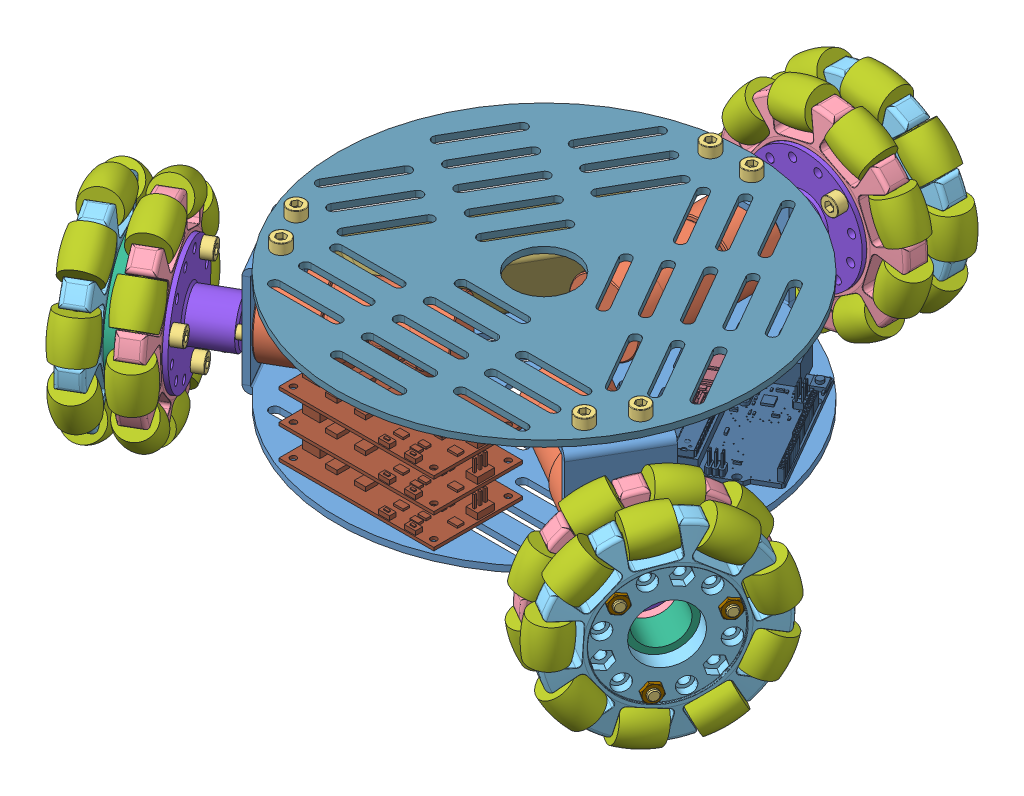
SolidWorks assembly mo-hinh-robot-new, configuration Default. Lengths in mm.
Overall size (364.36 149.81 350).
113 component instances, 14 part files, 37 mates.
Components (placement in the parent):
- khung duoi-1-2: khung duoi-1 [Default] at (-15.7838 -23.5823 19.2294) size (200 53 201.72)
- DC 12v 251rpm-1: DC 12v 251rpm [Default] at (-101.2746 -4.3589 68.5875) x (0.866025 0 -0.5) z (-0.5 0 -0.866025) size (90.8 37 37)
- socket head cap screw_iso-2: socket head cap screw_iso [ISO 4762 M3 x 5 - 5N] at (-98.7207 -4.3589 85.0109) x (0.866025 0 -0.5) z (0.5 0 0.866025) size (8 5.5 5.5)
- socket head cap screw_iso-3: socket head cap screw_iso [ISO 4762 M3 x 5 - 5N] at (-114.2207 -4.3589 58.1641) x (0.866025 0 -0.5) z (0.5 0 0.866025) size (8 5.5 5.5)
- banhxe-1: banhxe [Default] at (-204.1499 -59.7221 94.9057) x (-0.487142 0.225323 -0.843755) z (0.866025 0 -0.5) size (124.48 124.98 61.51)
  - omniwheel_1-1: omniwheel_1 [Default] at (-17.0114 53.5739 73.2518) size (91.98 90.63 15.09)
  - omniwheel_2-1: omniwheel_2 [Default] at (-17.0114 53.5739 37.2518) x (-0.5 -0.866025 0) z (0 0 -1) size (91.98 90.63 15.09)
  - Part1^banhxe-1: Part1^banhxe [Default] at (-17.0114 53.5739 59.2518) x (-1 0 0) z (0 0 -1) size (56.8 56.8 18) (virtual)
  - roller-1: roller [Default] at (-17.0114 132.3987 78.8462) x (1 0 0) z (0 0.323318 -0.94629) size (24.1 19 19)
  - roller-3: roller [Default] at (33.6561 113.9572 78.8462) x (0.766044 -0.642788 0) z (0.207825 0.247676 -0.94629) size (24.1 19 19)
  - roller-4: roller [Default] at (60.6158 67.2617 78.8462) x (0.173648 -0.984808 0) z (0.318406 0.056144 -0.94629) size (24.1 19 19)
  - roller-5: roller [Default] at (51.2528 14.1616 78.8462) x (-0.5 -0.866025 0) z (0.280001 -0.161659 -0.94629) size (24.1 19 19)
  - roller-6: roller [Default] at (9.9482 -20.4971 78.8462) x (-0.939693 -0.34202 0) z (0.110581 -0.303819 -0.94629) size (24.1 19 19)
  - roller-7: roller [Default] at (-43.9711 -20.4971 78.8462) x (-0.939693 0.34202 0) z (-0.110581 -0.303819 -0.94629) size (24.1 19 19)
  - roller-8: roller [Default] at (-85.2757 14.1616 78.8462) x (-0.5 0.866025 0) z (-0.280001 -0.161659 -0.94629) size (24.1 19 19)
  - roller-9: roller [Default] at (-94.6387 67.2617 78.8462) x (0.173648 0.984808 0) z (-0.318406 0.056144 -0.94629) size (24.1 19 19)
  - roller-10: roller [Default] at (-67.679 113.9572 78.8462) x (0.766044 0.642788 0) z (-0.207825 0.247676 -0.94629) size (24.1 19 19)
  - roller-11: roller [Default] at (-17.5454 53.8822 51.7918) x (0.5 0.866025 0) z (-0.150538 0.086913 0.984776) size (24.1 19 19)
  - roller-12: roller [Default] at (-17.6186 53.4669 51.7918) x (-0.173648 0.984808 0) z (-0.171186 -0.030185 0.984776) size (24.1 19 19)
  - roller-13: roller [Default] at (-17.4078 53.1016 51.7918) x (-0.766044 0.642788 0) z (-0.111734 -0.133159 0.984776) size (24.1 19 19)
  - roller-14: roller [Default] at (-17.0114 52.9574 51.7918) x (-1 0 0) z (0 -0.173827 0.984776) size (24.1 19 19)
  - roller-15: roller [Default] at (-16.6151 53.1016 51.7918) x (-0.766044 -0.642788 0) z (0.111734 -0.133159 0.984776) size (24.1 19 19)
  - roller-16: roller [Default] at (-16.4042 53.4669 51.7918) x (-0.173648 -0.984808 0) z (0.171186 -0.030185 0.984776) size (24.1 19 19)
  - roller-17: roller [Default] at (-16.4775 53.8822 51.7918) x (0.5 -0.866025 0) z (0.150538 0.086913 0.984776) size (24.1 19 19)
  - roller-18: roller [Default] at (-16.8006 54.1533 51.7918) x (0.939693 -0.34202 0) z (0.059452 0.163344 0.984776) size (24.1 19 19)
  - roller-19: roller [Default] at (-17.2223 54.1533 51.7918) x (0.939693 0.34202 0) z (-0.059452 0.163344 0.984776) size (24.1 19 19)
  - Part3^banhxe-1: Part3^banhxe [Default] at (-17.0114 53.5739 72.2518) size (56.8 56.8 23)
  - socket head cap screw_iso-2: socket head cap screw_iso [ISO 4762 M5 x 40 - 22C] at (-37.6228 65.4739 80.2518) x (0 0 -1) z (-0.98661 0.163099 0) size (45 8.5 8.5)
  - hex nut gradec_iso-1: hex nut gradec_iso [ISO - 4034 - M5 - N] at (-37.6228 65.4739 36.6518) x (0 -1 0) z (0 0 -1) size (8 9.24 5.6)
  - hex nut gradec_iso-2: hex nut gradec_iso [ISO - 4034 - M5 - N] at (-17.0114 29.7739 36.6518) x (0.866025 0.5 0) z (0 0 -1) size (8 9.24 5.6)
  - hex nut gradec_iso-3: hex nut gradec_iso [ISO - 4034 - M5 - N] at (3.6 65.4739 36.6518) x (-0.866025 0.5 0) z (0 0 -1) size (8 9.24 5.6)
  - socket head cap screw_iso-3: socket head cap screw_iso [ISO 4762 M5 x 40 - 22C] at (-17.0114 29.7739 80.2518) x (0 0 -1) z (0.352057 -0.935979 0) size (45 8.5 8.5)
  - socket head cap screw_iso-4: socket head cap screw_iso [ISO 4762 M5 x 40 - 22C] at (3.6 65.4739 80.2518) x (0 0 -1) z (0.634553 0.77288 0) size (45 8.5 8.5)
  - socket head cap screw_iso-7: socket head cap screw_iso [ISO 4762 M3 x 10 - 10C] at (-17.0114 39.5739 87.2518) x (0 1 0) z (-0.678428 0 0.734667) size (13 5.5 5.5)
- DC 12v 251rpm-2: DC 12v 251rpm [Default] at (69.7069 -4.3589 68.5875) x (-0.866025 0 -0.5) z (-0.5 0 0.866025) size (90.8 37 37)
- DC 12v 251rpm-3: DC 12v 251rpm [Default] at (-15.7838 -4.3589 -79.4868) x (0 0 1) z (1 0 0) size (90.8 37 37)
- socket head cap screw_iso-4: socket head cap screw_iso [ISO 4762 M3 x 5 - 5N] at (67.153 -4.3589 85.0109) x (-0.866025 0 -0.5) z (0.5 0 -0.866025) size (8 5.5 5.5)
- socket head cap screw_iso-5: socket head cap screw_iso [ISO 4762 M3 x 5 - 5N] at (-0.2838 -4.3589 -85.4868) x (0 0 1) z (-1 0 0) size (8 5.5 5.5)
- socket head cap screw_iso-6: socket head cap screw_iso [ISO 4762 M3 x 5 - 5N] at (82.653 -4.3589 58.1641) x (-0.866025 0 -0.5) z (0.5 0 -0.866025) size (8 5.5 5.5)
- socket head cap screw_iso-7: socket head cap screw_iso [ISO 4762 M3 x 5 - 5N] at (-31.2838 -4.3589 -85.4868) x (0 0 1) z (-1 0 0) size (8 5.5 5.5)
- banhxe-2: banhxe [Default] at (143.9368 -59.7221 144.5211) x (-0.487142 0.225323 0.843755) z (-0.866025 0 -0.5) size (124.48 124.98 61.51)
  - omniwheel_1-1: omniwheel_1 [Default] at (-17.0114 53.5739 73.2518) size (91.98 90.63 15.09)
  - omniwheel_2-1: omniwheel_2 [Default] at (-17.0114 53.5739 37.2518) x (-0.5 -0.866025 0) z (0 0 -1) size (91.98 90.63 15.09)
  - Part1^banhxe-1: Part1^banhxe [Default] at (-17.0114 53.5739 59.2518) x (-1 0 0) z (0 0 -1) size (56.8 56.8 18) (virtual)
  - roller-1: roller [Default] at (-17.0114 132.3987 78.8462) x (1 0 0) z (0 0.323318 -0.94629) size (24.1 19 19)
  - roller-3: roller [Default] at (33.6561 113.9572 78.8462) x (0.766044 -0.642788 0) z (0.207825 0.247676 -0.94629) size (24.1 19 19)
  - roller-4: roller [Default] at (60.6158 67.2617 78.8462) x (0.173648 -0.984808 0) z (0.318406 0.056144 -0.94629) size (24.1 19 19)
  - roller-5: roller [Default] at (51.2528 14.1616 78.8462) x (-0.5 -0.866025 0) z (0.280001 -0.161659 -0.94629) size (24.1 19 19)
  - roller-6: roller [Default] at (9.9482 -20.4971 78.8462) x (-0.939693 -0.34202 0) z (0.110581 -0.303819 -0.94629) size (24.1 19 19)
  - roller-7: roller [Default] at (-43.9711 -20.4971 78.8462) x (-0.939693 0.34202 0) z (-0.110581 -0.303819 -0.94629) size (24.1 19 19)
  - roller-8: roller [Default] at (-85.2757 14.1616 78.8462) x (-0.5 0.866025 0) z (-0.280001 -0.161659 -0.94629) size (24.1 19 19)
  - roller-9: roller [Default] at (-94.6387 67.2617 78.8462) x (0.173648 0.984808 0) z (-0.318406 0.056144 -0.94629) size (24.1 19 19)
  - roller-10: roller [Default] at (-67.679 113.9572 78.8462) x (0.766044 0.642788 0) z (-0.207825 0.247676 -0.94629) size (24.1 19 19)
  - roller-11: roller [Default] at (-17.5454 53.8822 51.7918) x (0.5 0.866025 0) z (-0.150538 0.086913 0.984776) size (24.1 19 19)
  - roller-12: roller [Default] at (-17.6186 53.4669 51.7918) x (-0.173648 0.984808 0) z (-0.171186 -0.030185 0.984776) size (24.1 19 19)
  - roller-13: roller [Default] at (-17.4078 53.1016 51.7918) x (-0.766044 0.642788 0) z (-0.111734 -0.133159 0.984776) size (24.1 19 19)
  - roller-14: roller [Default] at (-17.0114 52.9574 51.7918) x (-1 0 0) z (0 -0.173827 0.984776) size (24.1 19 19)
  - roller-15: roller [Default] at (-16.6151 53.1016 51.7918) x (-0.766044 -0.642788 0) z (0.111734 -0.133159 0.984776) size (24.1 19 19)
  - roller-16: roller [Default] at (-16.4042 53.4669 51.7918) x (-0.173648 -0.984808 0) z (0.171186 -0.030185 0.984776) size (24.1 19 19)
  - roller-17: roller [Default] at (-16.4775 53.8822 51.7918) x (0.5 -0.866025 0) z (0.150538 0.086913 0.984776) size (24.1 19 19)
  - roller-18: roller [Default] at (-16.8006 54.1533 51.7918) x (0.939693 -0.34202 0) z (0.059452 0.163344 0.984776) size (24.1 19 19)
  - roller-19: roller [Default] at (-17.2223 54.1533 51.7918) x (0.939693 0.34202 0) z (-0.059452 0.163344 0.984776) size (24.1 19 19)
  - Part3^banhxe-1: Part3^banhxe [Default] at (-17.0114 53.5739 72.2518) size (56.8 56.8 23)
  - socket head cap screw_iso-2: socket head cap screw_iso [ISO 4762 M5 x 40 - 22C] at (-37.6228 65.4739 80.2518) x (0 0 -1) z (-0.98661 0.163099 0) size (45 8.5 8.5)
  - hex nut gradec_iso-1: hex nut gradec_iso [ISO - 4034 - M5 - N] at (-37.6228 65.4739 36.6518) x (0 -1 0) z (0 0 -1) size (8 9.24 5.6)
  - hex nut gradec_iso-2: hex nut gradec_iso [ISO - 4034 - M5 - N] at (-17.0114 29.7739 36.6518) x (0.866025 0.5 0) z (0 0 -1) size (8 9.24 5.6)
  - hex nut gradec_iso-3: hex nut gradec_iso [ISO - 4034 - M5 - N] at (3.6 65.4739 36.6518) x (-0.866025 0.5 0) z (0 0 -1) size (8 9.24 5.6)
  - socket head cap screw_iso-3: socket head cap screw_iso [ISO 4762 M5 x 40 - 22C] at (-17.0114 29.7739 80.2518) x (0 0 -1) z (0.352057 -0.935979 0) size (45 8.5 8.5)
  - socket head cap screw_iso-4: socket head cap screw_iso [ISO 4762 M5 x 40 - 22C] at (3.6 65.4739 80.2518) x (0 0 -1) z (0.634553 0.77288 0) size (45 8.5 8.5)
  - socket head cap screw_iso-7: socket head cap screw_iso [ISO 4762 M3 x 10 - 10C] at (-17.0114 39.5739 87.2518) x (0 1 0) z (-0.678428 0 0.734667) size (13 5.5 5.5)
- banhxe-3: banhxe [Default] at (12.8616 -59.7221 -181.7386) x (0.974284 0.225323 0) z (0 0 1) size (124.48 124.98 61.51)
  - omniwheel_1-1: omniwheel_1 [Default] at (-17.0114 53.5739 73.2518) size (91.98 90.63 15.09)
  - omniwheel_2-1: omniwheel_2 [Default] at (-17.0114 53.5739 37.2518) x (-0.5 -0.866025 0) z (0 0 -1) size (91.98 90.63 15.09)
  - Part1^banhxe-1: Part1^banhxe [Default] at (-17.0114 53.5739 59.2518) x (-1 0 0) z (0 0 -1) size (56.8 56.8 18) (virtual)
  - roller-1: roller [Default] at (-17.0114 132.3987 78.8462) x (1 0 0) z (0 0.323318 -0.94629) size (24.1 19 19)
  - roller-3: roller [Default] at (33.6561 113.9572 78.8462) x (0.766044 -0.642788 0) z (0.207825 0.247676 -0.94629) size (24.1 19 19)
  - roller-4: roller [Default] at (60.6158 67.2617 78.8462) x (0.173648 -0.984808 0) z (0.318406 0.056144 -0.94629) size (24.1 19 19)
  - roller-5: roller [Default] at (51.2528 14.1616 78.8462) x (-0.5 -0.866025 0) z (0.280001 -0.161659 -0.94629) size (24.1 19 19)
  - roller-6: roller [Default] at (9.9482 -20.4971 78.8462) x (-0.939693 -0.34202 0) z (0.110581 -0.303819 -0.94629) size (24.1 19 19)
  - roller-7: roller [Default] at (-43.9711 -20.4971 78.8462) x (-0.939693 0.34202 0) z (-0.110581 -0.303819 -0.94629) size (24.1 19 19)
  - roller-8: roller [Default] at (-85.2757 14.1616 78.8462) x (-0.5 0.866025 0) z (-0.280001 -0.161659 -0.94629) size (24.1 19 19)
  - roller-9: roller [Default] at (-94.6387 67.2617 78.8462) x (0.173648 0.984808 0) z (-0.318406 0.056144 -0.94629) size (24.1 19 19)
  - roller-10: roller [Default] at (-67.679 113.9572 78.8462) x (0.766044 0.642788 0) z (-0.207825 0.247676 -0.94629) size (24.1 19 19)
  - roller-11: roller [Default] at (-17.5454 53.8822 51.7918) x (0.5 0.866025 0) z (-0.150538 0.086913 0.984776) size (24.1 19 19)
  - roller-12: roller [Default] at (-17.6186 53.4669 51.7918) x (-0.173648 0.984808 0) z (-0.171186 -0.030185 0.984776) size (24.1 19 19)
  - roller-13: roller [Default] at (-17.4078 53.1016 51.7918) x (-0.766044 0.642788 0) z (-0.111734 -0.133159 0.984776) size (24.1 19 19)
  - roller-14: roller [Default] at (-17.0114 52.9574 51.7918) x (-1 0 0) z (0 -0.173827 0.984776) size (24.1 19 19)
  - roller-15: roller [Default] at (-16.6151 53.1016 51.7918) x (-0.766044 -0.642788 0) z (0.111734 -0.133159 0.984776) size (24.1 19 19)
  - roller-16: roller [Default] at (-16.4042 53.4669 51.7918) x (-0.173648 -0.984808 0) z (0.171186 -0.030185 0.984776) size (24.1 19 19)
  - roller-17: roller [Default] at (-16.4775 53.8822 51.7918) x (0.5 -0.866025 0) z (0.150538 0.086913 0.984776) size (24.1 19 19)
  - roller-18: roller [Default] at (-16.8006 54.1533 51.7918) x (0.939693 -0.34202 0) z (0.059452 0.163344 0.984776) size (24.1 19 19)
  - roller-19: roller [Default] at (-17.2223 54.1533 51.7918) x (0.939693 0.34202 0) z (-0.059452 0.163344 0.984776) size (24.1 19 19)
  - Part3^banhxe-1: Part3^banhxe [Default] at (-17.0114 53.5739 72.2518) size (56.8 56.8 23)
  - socket head cap screw_iso-2: socket head cap screw_iso [ISO 4762 M5 x 40 - 22C] at (-37.6228 65.4739 80.2518) x (0 0 -1) z (-0.98661 0.163099 0) size (45 8.5 8.5)
  - hex nut gradec_iso-1: hex nut gradec_iso [ISO - 4034 - M5 - N] at (-37.6228 65.4739 36.6518) x (0 -1 0) z (0 0 -1) size (8 9.24 5.6)
  - hex nut gradec_iso-2: hex nut gradec_iso [ISO - 4034 - M5 - N] at (-17.0114 29.7739 36.6518) x (0.866025 0.5 0) z (0 0 -1) size (8 9.24 5.6)
  - hex nut gradec_iso-3: hex nut gradec_iso [ISO - 4034 - M5 - N] at (3.6 65.4739 36.6518) x (-0.866025 0.5 0) z (0 0 -1) size (8 9.24 5.6)
  - socket head cap screw_iso-3: socket head cap screw_iso [ISO 4762 M5 x 40 - 22C] at (-17.0114 29.7739 80.2518) x (0 0 -1) z (0.352057 -0.935979 0) size (45 8.5 8.5)
  - socket head cap screw_iso-4: socket head cap screw_iso [ISO 4762 M5 x 40 - 22C] at (3.6 65.4739 80.2518) x (0 0 -1) z (0.634553 0.77288 0) size (45 8.5 8.5)
  - socket head cap screw_iso-7: socket head cap screw_iso [ISO 4762 M3 x 10 - 10C] at (-17.0114 39.5739 87.2518) x (0 1 0) z (-0.678428 0 0.734667) size (13 5.5 5.5)
- Arduino UNO-1: Arduino UNO [Predeterminado] at (41.1207 -23.5823 -18.8206) x (0.5 0 0.866025) z (-0.866025 0 0.5) size (75 12 51.02)
- DRIVER-cytron-1: DRIVER-cytron [Default] at (-53.2838 -23.5823 110.0884) size (75 10.5 43)
- DRIVER-cytron-2: DRIVER-cytron [Default] at (-53.2838 -8.5823 110.0884) size (75 10.5 43)
- DRIVER-cytron-3: DRIVER-cytron [Default] at (-53.2838 6.4177 110.0884) size (75 10.5 43)
- pin li-po-1: pin li-po [Default] at (-73.3745 -23.5823 -14.0206) x (0.5 0 -0.866025) z (0.866025 0 0.5) size (105 23 32)
- HC-06-1: HC-06 [Predeterminado] at (34.603 -3.5823 -8.8739) x (0.5 0 0.866025) z (-0.866025 0 0.5) size (42.75 6.1 15)
- khung tren-2: khung tren [Default] at (-15.7838 26.4211 19.2294) size (200 3 200)
- socket head cap screw_iso-8: socket head cap screw_iso [ISO 4762 M5 x 8 - 8N] at (-89.1905 34.4211 73.1578) x (0 -1 0) z (0 0 1) size (13 8.5 8.5)
- socket head cap screw_iso-9: socket head cap screw_iso [ISO 4762 M5 x 8 - 8N] at (-99.1905 34.4211 55.8373) x (0 -1 0) z (0 0 1) size (13 8.5 8.5)
- socket head cap screw_iso-10: socket head cap screw_iso [ISO 4762 M5 x 8 - 8N] at (67.6228 34.4211 55.8373) x (0 -1 0) z (0 0 1) size (13 8.5 8.5)
- socket head cap screw_iso-11: socket head cap screw_iso [ISO 4762 M5 x 8 - 8N] at (57.6228 34.4211 73.1578) x (0 -1 0) z (0 0 1) size (13 8.5 8.5)
- socket head cap screw_iso-12: socket head cap screw_iso [ISO 4762 M5 x 8 - 8N] at (-25.7838 34.4211 -71.3068) x (0 -1 0) z (0 0 1) size (13 8.5 8.5)
- socket head cap screw_iso-13: socket head cap screw_iso [ISO 4762 M5 x 8 - 8N] at (-5.7838 34.4211 -71.3068) x (0 -1 0) z (0 0 1) size (13 8.5 8.5)
Mates (geometry in assembly coordinates):
- Concentric1: concentric aligned: cylinder of khung duoi-1-2 through (-103.8726 -11.3589 70.0875) axis (0.866025 0 -0.5) radius 6.2; cylinder of DC 12v 251rpm-1 through (-106.2975 -11.3589 71.4875) axis (0.866025 0 -0.5) radius 6
- Coincident1: coincident anti-aligned: plane of khung duoi-1-2 through (-101.2746 -124.3385 68.5875) normal (0.866025 0 -0.5); plane of DC 12v 251rpm-1 through (-101.2746 -4.3589 68.5875) normal (-0.866025 0 0.5)
- Concentric2: concentric anti-aligned: circle of khung duoi-1-2; circle of DC 12v 251rpm-1
- Concentric3: concentric anti-aligned: cylinder of khung duoi-1-2 through (-96.1226 -4.3589 83.5109) axis (0.866025 0 -0.5) radius 1.6; cylinder of socket head cap screw_iso-2 through (-126.217 -4.3589 100.8859) axis (-0.866025 0 0.5) radius 2.75
- Coincident3: coincident anti-aligned: plane of khung duoi-1-2 through (-103.8726 -124.3385 70.0875) normal (-0.866025 0 0.5); plane of socket head cap screw_iso-2 through (-96.1226 -1.6089 83.5109) normal (0.866025 0 -0.5)
- Concentric4: concentric anti-aligned: cylinder of khung duoi-1-2 through (-111.6226 -4.3589 56.6641) axis (0.866025 0 -0.5) radius 1.6; cylinder of socket head cap screw_iso-3 through (-141.717 -4.3589 74.0391) axis (-0.866025 0 0.5) radius 2.75
- Coincident4: coincident anti-aligned: plane of khung duoi-1-2 through (-103.8726 -124.3385 70.0875) normal (-0.866025 0 0.5); plane of socket head cap screw_iso-3 through (-111.6226 -1.6089 56.6641) normal (0.866025 0 -0.5)
- Concentric5: concentric aligned: cylinder of DC 12v 251rpm-1 through (-119.4611 -11.3589 79.0875) axis (0.866025 0 -0.5) radius 3; cylinder of banhxe-1/Part3^banhxe-1 through (-127.2553 -11.3589 83.5875) axis (0.866025 0 -0.5) radius 3
- Distance1: distance = 4 mm anti-aligned: plane of khung duoi-1-2 through (-103.8726 -124.3385 70.0875) normal (-0.866025 0 0.5); plane of banhxe-1/Part3^banhxe-1 through (-107.3367 -11.3589 72.0875) normal (0.866025 0 -0.5)
- Coincident6: coincident anti-aligned: plane of khung duoi-1-2 through (-15.7838 -23.5823 19.2294) normal (0 1 0); plane of DRIVER-cytron-1 through (-53.2838 -23.5823 110.0884) normal (0 -1 0)
- Tangent3: tangent aligned: plane of khung duoi-1-2 through (44.2162 -26.5823 72.0884) normal (0 0 1); cylinder of DRIVER-cytron-1 through (18.2162 -23.5823 70.5884) axis (0 1 0) radius 1.5
- Tangent4: tangent aligned: plane of khung duoi-1-2 through (-45.7838 -26.5823 72.0884) normal (0 0 1); cylinder of DRIVER-cytron-1 through (-49.7838 -23.5823 70.5884) axis (0 1 0) radius 1.5
- Width1: width anti-aligned: plane of khung duoi-1-2 through (4.2162 26.4211 -61.3068) normal (1 0 0); plane of khung duoi-1-2 through (-35.7838 26.4211 -131.3068) normal (-1 0 0); plane of DRIVER-cytron-1 through (-53.2838 -22.0823 110.0884) normal (-1 0 0); plane of DRIVER-cytron-1 through (21.7162 -22.0823 110.0884) normal (1 0 0)
- Coincident7: coincident anti-aligned: plane of khung duoi-1-2 through (-15.7838 -23.5823 19.2294) normal (0 1 0); plane of Arduino UNO-1 through (41.1207 -23.5823 -18.8206) normal (0 -1 0)
- Coincident8: coincident aligned: plane of khung duoi-1-2 through (13.5222 -26.5823 -15.011) normal (-0.866025 0 0.5); plane of Arduino UNO-1 through (27.0292 -32.5823 8.3838) normal (-0.866025 0 0.5)
- Distance2: distance = 3 mm: line of khung duoi-1-2 through (57.9838 -26.5823 11.2807) axis (0 1 0); plane of Arduino UNO-1 through (82.3874 -21.5823 0.6553) normal (0.5 0 0.866025)
- Coincident9: coincident anti-aligned: plane of khung duoi-1-2 through (-15.7838 -23.5823 19.2294) normal (0 1 0); plane of pin li-po-1 through (-73.3745 -23.5823 -14.0206) normal (0 -1 0)
- Coincident10: coincident aligned: plane of khung duoi-1-2 through (-94.7309 -26.5823 -9.0302) normal (-0.866025 0 -0.5); plane of pin li-po-1 through (-113.4809 -0.5823 23.4457) normal (-0.866025 0 -0.5)
- Width2: width aligned: plane of pin li-po-1 through (-85.7681 -0.5823 39.4457) normal (-0.5 0 0.866025); plane of pin li-po-1 through (-33.2681 -0.5823 -51.4869) normal (0.5 0 -0.866025); plane of khung duoi-1-2 through (43.9626 26.4211 76.818) normal (-0.5 0 0.866025); plane of khung duoi-1-2 through (124.5844 26.4211 77.177) normal (0.5 0 -0.866025)
- Distance3: distance = 20 mm anti-aligned: plane of HC-06-1 through (34.603 -3.5823 -8.8739) normal (0 -1 0); plane of khung duoi-1-2 through (-15.7838 -23.5823 19.2294) normal (0 1 0)
- Width3: width aligned: plane of HC-06-1 through (50.5982 -1.5823 3.8306) normal (0.866025 0 -0.5); plane of HC-06-1 through (18.6078 -1.5823 -21.5784) normal (-0.866025 0 0.5); plane of Arduino UNO-1 through (35.1153 -17.5823 -17.7723) normal (0.866025 0 -0.5); plane of Arduino UNO-1 through (26.6405 -17.5823 -12.8794) normal (-0.866025 0 0.5)
- Distance4: distance = 10 mm aligned: plane of HC-06-1 through (37.6078 -1.5823 11.3306) normal (0.5 0 0.866025); plane of Arduino UNO-1 through (53.3404 -17.5823 13.7944) normal (0.5 0 0.866025)
- Coincident11: coincident anti-aligned: plane of khung duoi-1-2 through (199.4372 26.4211 143.4873) normal (0 1 0); plane of khung tren-2 through (-15.7838 26.4211 19.2294) normal (0 -1 0)
- Coincident12: coincident aligned: plane of khung duoi-1-2 through (44.2162 -26.5823 72.0884) normal (0 0 1); plane of khung tren-2 through (44.2162 26.4211 72.0884) normal (0 0 1)
- Concentric6: concentric aligned: circle of khung duoi-1-2; circle of khung tren-2
- Concentric7: concentric aligned: cylinder of khung tren-2 through (-89.1905 26.4211 73.1578) axis (0 1 0) radius 2.1; cylinder of socket head cap screw_iso-8 through (-89.1905 66.1711 73.1578) axis (0 1 0) radius 4.25
- Coincident13: coincident anti-aligned: plane of khung tren-2 through (-15.7838 29.4211 19.2294) normal (0 1 0); plane of socket head cap screw_iso-8 through (-84.9405 29.4211 73.1578) normal (0 -1 0)
- Concentric8: concentric aligned: cylinder of khung tren-2 through (-99.1905 26.4211 55.8373) axis (0 1 0) radius 2.1; cylinder of socket head cap screw_iso-9 through (-99.1905 66.1711 55.8373) axis (0 1 0) radius 4.25
- Coincident14: coincident anti-aligned: plane of khung tren-2 through (-15.7838 29.4211 19.2294) normal (0 1 0); plane of socket head cap screw_iso-9 through (-94.9405 29.4211 55.8373) normal (0 -1 0)
- Concentric9: concentric aligned: cylinder of khung tren-2 through (67.6228 26.4211 55.8373) axis (0 1 0) radius 2.1; cylinder of socket head cap screw_iso-10 through (67.6228 66.1711 55.8373) axis (0 1 0) radius 4.25
- Coincident15: coincident anti-aligned: plane of khung tren-2 through (-15.7838 29.4211 19.2294) normal (0 1 0); plane of socket head cap screw_iso-10 through (71.8728 29.4211 55.8373) normal (0 -1 0)
- Concentric10: concentric aligned: cylinder of khung tren-2 through (57.6228 26.4211 73.1578) axis (0 1 0) radius 2.1; cylinder of socket head cap screw_iso-11 through (57.6228 66.1711 73.1578) axis (0 1 0) radius 4.25
- Coincident16: coincident anti-aligned: plane of khung tren-2 through (-15.7838 29.4211 19.2294) normal (0 1 0); plane of socket head cap screw_iso-11 through (61.8728 29.4211 73.1578) normal (0 -1 0)
- Concentric11: concentric aligned: cylinder of khung tren-2 through (-25.7838 26.4211 -71.3068) axis (0 1 0) radius 2.1; cylinder of socket head cap screw_iso-12 through (-25.7838 66.1711 -71.3068) axis (0 1 0) radius 4.25
- Coincident17: coincident anti-aligned: plane of khung tren-2 through (-15.7838 29.4211 19.2294) normal (0 1 0); plane of socket head cap screw_iso-12 through (-21.5338 29.4211 -71.3068) normal (0 -1 0)
- Concentric12: concentric aligned: cylinder of khung tren-2 through (-5.7838 26.4211 -71.3068) axis (0 1 0) radius 2.1; cylinder of socket head cap screw_iso-13 through (-5.7838 66.1711 -71.3068) axis (0 1 0) radius 4.25
- Coincident18: coincident anti-aligned: plane of khung tren-2 through (-15.7838 29.4211 19.2294) normal (0 1 0); plane of socket head cap screw_iso-13 through (-1.5338 29.4211 -71.3068) normal (0 -1 0)
